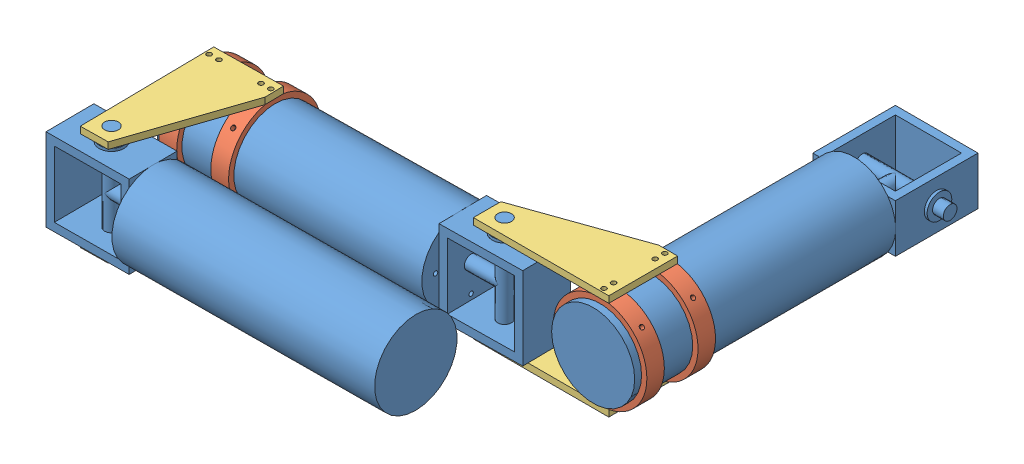
SolidWorks assembly EnsamblajeBrazoV2_2, configuration Predeterminado. Lengths in mm.
Overall size (360.92 97.75 347.04).
11 component instances, 3 part files, 26 mates.
Components (placement in the parent):
- EslabonSimplificado-1: EslabonSimplificado [Predeterminado] at origin size (79.5 60.33 249.5)
- SujeccionMotorV2-1: SujeccionMotorV2 [Predeterminado] at (0 0 208.15) x (0.707107 -0.707107 0) z (0 0 1) size (68 68 12.7)
- SujeccionMotorV2-2: SujeccionMotorV2 [Predeterminado] at (0 0 171) x (0.707107 -0.707107 0) z (0 0 1) size (68 68 12.7)
- Soporte-3: Soporte [Predeterminado] at (6.35 33.4018 214.5) x (0 0 1) z (0 1 0) size (50 98.35 4.76)
- Soporte-4: Soporte [Predeterminado] at (6.35 -38.1643 214.5) x (0 0 1) z (0 1 0) size (50 98.35 4.76)
- EslabonSimplificado-2: EslabonSimplificado [Predeterminado] at (-80.65 -1.5857 203.15) x (0 1 0) z (-0.999899 0 0.014183) size (79.5 60.33 249.5)
- SujeccionMotorV2-3: SujeccionMotorV2 [Predeterminado] at (-288.7791 -1.5857 206.1023) x (0.010029 -0.707107 0.707036) z (-0.999899 0 0.014183) size (68 68 12.7)
- SujeccionMotorV2-4: SujeccionMotorV2 [Predeterminado] at (-251.6328 -1.5857 205.5754) x (0.010029 -0.707107 0.707036) z (-0.999899 0 0.014183) size (68 68 12.7)
- Soporte-7: Soporte [Predeterminado] at (-295.2185 36.5785 199.843) x (-0.999899 0 0.014183) z (0 -1 0) size (50 98.35 4.76)
- Soporte-8: Soporte [Predeterminado] at (-295.2185 -34.9875 199.843) x (-0.999899 0 0.014183) z (0 -1 0) size (50 98.35 4.76)
- EslabonSimplificado-4: EslabonSimplificado [Predeterminado] at (-282.6357 -3.1715 286.6733) x (0 1 0) z (0.999977 0 -0.006844) size (79.5 60.33 249.5)
Mates (geometry in assembly coordinates):
- Concéntrica1: concentric aligned: cylinder of EslabonSimplificado-1 through (0 0 30) axis (0 0 1) radius 30.165; cylinder of SujeccionMotorV2-1 through (0 0 201.8) axis (0 0 1) radius 30
- Paralelo1: parallel aligned: plane of EslabonSimplificado-1 through (0 17.5 0) normal (0 1 0); plane of SujeccionMotorV2-1 through (6.35 33.4018 201.8) normal (0 1 0)
- Concéntrica21: concentric aligned: cylinder of EslabonSimplificado-1 through (0 0 30) axis (0 0 1) radius 30.165; cylinder of SujeccionMotorV2-2 through (0 0 164.65) axis (0 0 1) radius 34
- Paralelo2: parallel aligned: plane of SujeccionMotorV2-1 through (6.35 33.4018 201.8) normal (0 1 0); plane of SujeccionMotorV2-2 through (6.35 33.4018 164.65) normal (0 1 0)
- Concéntrica7: concentric anti-aligned: cylinder of SujeccionMotorV2-1 through (0 -48.0833 204.65) axis (0 1 0) radius 1.75; cylinder of Soporte-3 through (0 38.1643 204.65) axis (0 -1 0) radius 1.75
- Concéntrica8: concentric anti-aligned: cylinder of SujeccionMotorV2-2 through (0 -48.0833 167.5) axis (0 1 0) radius 1.75; cylinder of Soporte-3 through (0 38.1643 167.5) axis (0 -1 0) radius 1.75
- Coincidente4: coincident anti-aligned: plane of SujeccionMotorV2-1 through (6.35 33.4018 201.8) normal (0 1 0); plane of Soporte-3 through (6.35 33.4018 214.5) normal (0 -1 0)
- Concéntrica9: concentric anti-aligned: cylinder of SujeccionMotorV2-2 through (0 -48.0833 167.5) axis (0 1 0) radius 1.75; cylinder of Soporte-4 through (0 -33.4018 167.5) axis (0 -1 0) radius 1.75
- Concéntrica10: concentric anti-aligned: cylinder of SujeccionMotorV2-1 through (0 -48.0833 211.65) axis (0 1 0) radius 1.75; cylinder of Soporte-4 through (0 -33.4018 211.65) axis (0 -1 0) radius 1.75
- Coincidente5: coincident anti-aligned: plane of SujeccionMotorV2-1 through (6.35 -33.4018 201.8) normal (0 -1 0); plane of Soporte-4 through (6.35 -33.4018 214.5) normal (0 1 0)
- Concéntrica11: concentric anti-aligned: cylinder of Soporte-3 through (-80.65 38.1643 203.15) axis (0 -1 0) radius 5; cylinder of EslabonSimplificado-2 through (-80.65 -64.5857 203.15) axis (0 1 0) radius 5
- Coincidente6: coincident aligned: plane of Soporte-3 through (6.35 38.1643 214.5) normal (0 1 0); plane of EslabonSimplificado-2 through (-80.65 38.1643 203.15) normal (0 1 0)
- Concéntrica121: concentric aligned: cylinder of EslabonSimplificado-2 through (-110.647 -1.5857 203.5755) axis (-0.999899 0 0.014183) radius 30.165; cylinder of SujeccionMotorV2-3 through (-282.4297 -1.5857 206.0122) axis (-0.999899 0 0.014183) radius 34
- Concéntrica131: concentric aligned: cylinder of EslabonSimplificado-2 through (-110.647 -1.5857 203.5755) axis (-0.999899 0 0.014183) radius 30.165; cylinder of SujeccionMotorV2-4 through (-245.2834 -1.5857 205.4853) axis (-0.999899 0 0.014183) radius 34
- Paralelo3: parallel aligned: plane of SujeccionMotorV2-3 through (-282.3396 31.816 212.3616) normal (0 1 0); plane of SujeccionMotorV2-4 through (-245.1934 31.816 211.8347) normal (0 1 0)
- Paralelo4: parallel aligned: plane of EslabonSimplificado-2 through (-50.4048 28.4143 220.2227) normal (0 1 0); plane of SujeccionMotorV2-4 through (-245.1934 31.816 211.8347) normal (0 1 0)
- Concéntrica19: concentric aligned: cylinder of SujeccionMotorV2-3 through (-292.2787 -49.669 206.1519) axis (0 1 0) radius 1.75; cylinder of Soporte-7 through (-292.2787 31.816 206.1519) axis (0 1 0) radius 1.75
- Concéntrica20: concentric aligned: cylinder of SujeccionMotorV2-4 through (-248.1332 -49.669 205.5257) axis (0 1 0) radius 1.75; cylinder of Soporte-7 through (-248.1332 31.816 205.5257) axis (0 1 0) radius 1.75
- Coincidente11: coincident anti-aligned: plane of SujeccionMotorV2-4 through (-245.1934 31.816 211.8347) normal (0 1 0); plane of Soporte-7 through (-295.2185 31.816 199.843) normal (0 -1 0)
- Concéntrica21: concentric aligned: cylinder of SujeccionMotorV2-4 through (-248.1332 -49.669 205.5257) axis (0 1 0) radius 1.75; cylinder of Soporte-8 through (-248.1332 -39.75 205.5257) axis (0 1 0) radius 1.75
- Concéntrica22: concentric aligned: cylinder of SujeccionMotorV2-3 through (-292.2787 -49.669 206.1519) axis (0 1 0) radius 1.75; cylinder of Soporte-8 through (-292.2787 -39.75 206.1519) axis (0 1 0) radius 1.75
- Coincidente12: coincident anti-aligned: plane of SujeccionMotorV2-3 through (-282.3396 -34.9875 212.3616) normal (0 -1 0); plane of Soporte-8 through (-295.2185 -34.9875 199.843) normal (0 1 0)
- Concéntrica23: concentric aligned: cylinder of Soporte-7 through (-282.6357 31.816 286.6733) axis (0 1 0) radius 5; cylinder of EslabonSimplificado-4 through (-282.6357 -66.1715 286.6733) axis (0 1 0) radius 5
- Coincidente13: coincident aligned: plane of Soporte-7 through (-295.2185 36.5785 199.843) normal (0 1 0); plane of EslabonSimplificado-4 through (-282.6357 36.5785 286.6733) normal (0 1 0)
- Distancia1: distance = 5 mm aligned: plane of EslabonSimplificado-1 through (0 0 219.5) normal (0 0 1); plane of SujeccionMotorV2-1 through (0 0 214.5) normal (0 0 1)
- Distancia2: distance = 5 mm aligned: plane of SujeccionMotorV2-3 through (-295.1284 -1.5857 206.1923) normal (-0.999899 0 0.014183); plane of EslabonSimplificado-2 through (-300.1279 -1.5857 206.2633) normal (-0.999899 0 0.014183)
